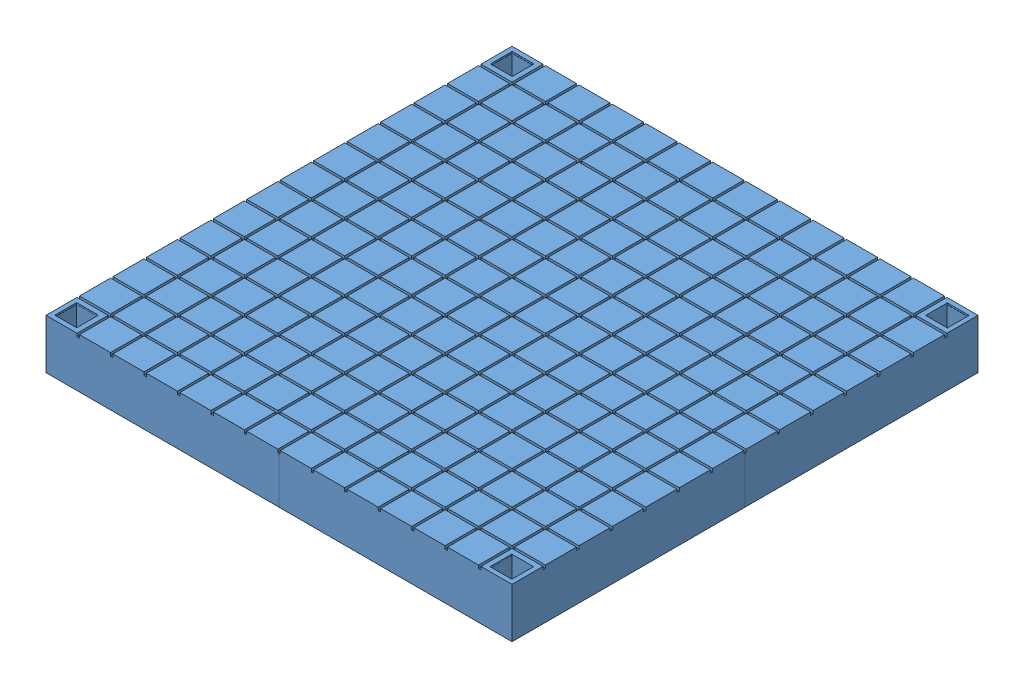
SolidWorks assembly R-02-01, configuration Default. Lengths in mm.
Overall size (300 32 300).
4 component instances, 1 part files, 0 mates.
Components (placement in the parent):
- Radiateur_placeholder-1: Radiateur_placeholder [Default] at (-121.3218 0.1156 88.4947) size (150 32 150)
- Radiateur_placeholder-2: Radiateur_placeholder [Default] at (178.6782 0.1156 88.4947) x (0 0 -1) z (1 0 0) size (150 32 150)
- Radiateur_placeholder-3: Radiateur_placeholder [Default] at (178.6782 0.1156 -211.5053) x (-1 0 0) z (0 0 -1) size (150 32 150)
- Radiateur_placeholder-4: Radiateur_placeholder [Default] at (-121.3218 0.1156 -211.5053) x (0 0 1) z (-1 0 0) size (150 32 150)
